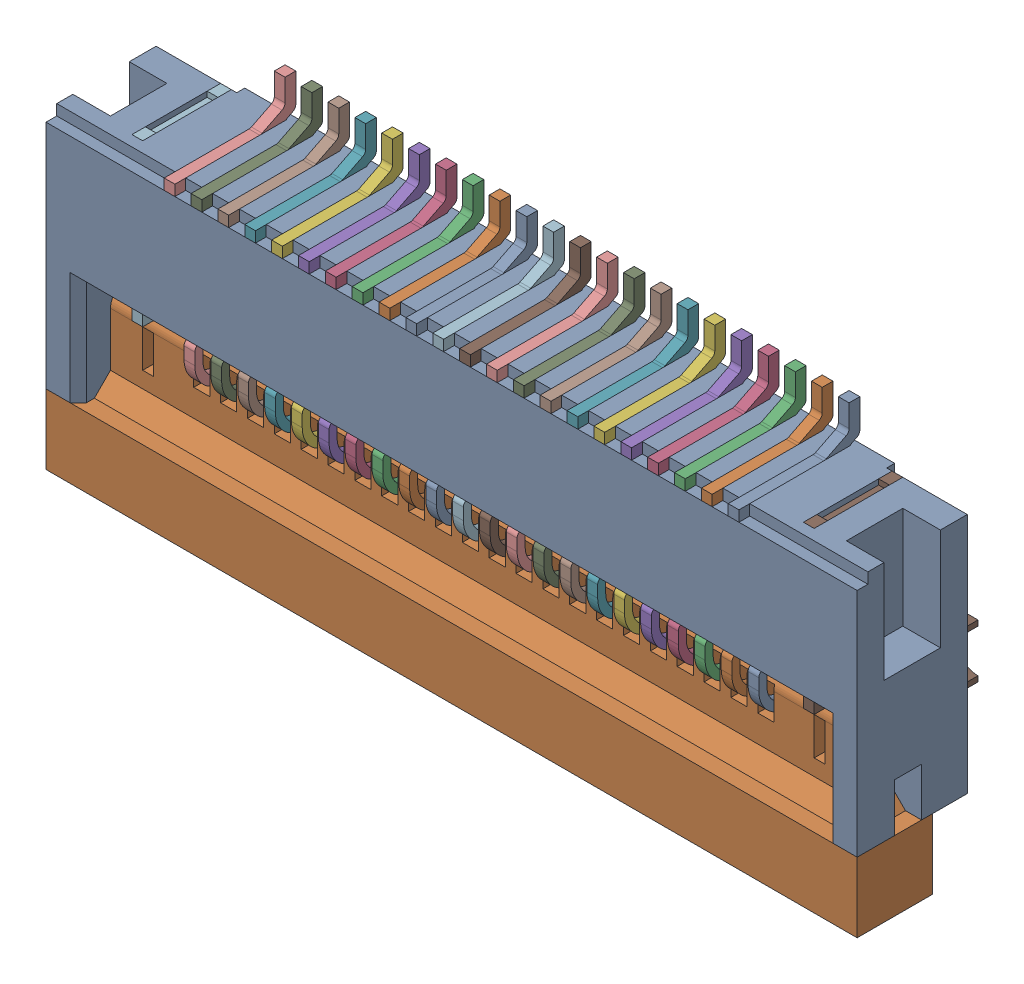
SolidWorks assembly 687122149022, configuration Default. Lengths in mm.
Overall size (15.1 6.5 2.25).
26 component instances, 5 part files, 0 mates.
Components (placement in the parent):
- 6871xx149022_Pin-1: 6871xx149022_Pin [Default] at (5.35 1.125 0.2986) x (-1 0 0) z (0 0 -1) size (0.2 4.6 2.25)
- 6871xx149022_Pin-2: 6871xx149022_Pin [Default] at (4.85 1.125 0.2986) x (-1 0 0) z (0 0 -1) size (0.2 4.6 2.25)
- 6871xx149022_Pin-3: 6871xx149022_Pin [Default] at (4.35 1.125 0.2986) x (-1 0 0) z (0 0 -1) size (0.2 4.6 2.25)
- 6871xx149022_Pin-4: 6871xx149022_Pin [Default] at (3.85 1.125 0.2986) x (-1 0 0) z (0 0 -1) size (0.2 4.6 2.25)
- 6871xx149022_Pin-5: 6871xx149022_Pin [Default] at (3.35 1.125 0.2986) x (-1 0 0) z (0 0 -1) size (0.2 4.6 2.25)
- 6871xx149022_Pin-6: 6871xx149022_Pin [Default] at (2.85 1.125 0.2986) x (-1 0 0) z (0 0 -1) size (0.2 4.6 2.25)
- 6871xx149022_Pin-7: 6871xx149022_Pin [Default] at (2.35 1.125 0.2986) x (-1 0 0) z (0 0 -1) size (0.2 4.6 2.25)
- 6871xx149022_Pin-8: 6871xx149022_Pin [Default] at (1.85 1.125 0.2986) x (-1 0 0) z (0 0 -1) size (0.2 4.6 2.25)
- 6871xx149022_Pin-9: 6871xx149022_Pin [Default] at (1.35 1.125 0.2986) x (-1 0 0) z (0 0 -1) size (0.2 4.6 2.25)
- 6871xx149022_Pin-10: 6871xx149022_Pin [Default] at (0.85 1.125 0.2986) x (-1 0 0) z (0 0 -1) size (0.2 4.6 2.25)
- 6871xx149022_Pin-11: 6871xx149022_Pin [Default] at (0.35 1.125 0.2986) x (-1 0 0) z (0 0 -1) size (0.2 4.6 2.25)
- 6871xx149022_Pin-12: 6871xx149022_Pin [Default] at (-0.15 1.125 0.2986) x (-1 0 0) z (0 0 -1) size (0.2 4.6 2.25)
- 6871xx149022_Pin-13: 6871xx149022_Pin [Default] at (-0.65 1.125 0.2986) x (-1 0 0) z (0 0 -1) size (0.2 4.6 2.25)
- 6871xx149022_Pin-14: 6871xx149022_Pin [Default] at (-1.15 1.125 0.2986) x (-1 0 0) z (0 0 -1) size (0.2 4.6 2.25)
- 6871xx149022_Pin-15: 6871xx149022_Pin [Default] at (-1.65 1.125 0.2986) x (-1 0 0) z (0 0 -1) size (0.2 4.6 2.25)
- 6871xx149022_Pin-16: 6871xx149022_Pin [Default] at (-2.15 1.125 0.2986) x (-1 0 0) z (0 0 -1) size (0.2 4.6 2.25)
- 6871xx149022_Pin-17: 6871xx149022_Pin [Default] at (-2.65 1.125 0.2986) x (-1 0 0) z (0 0 -1) size (0.2 4.6 2.25)
- 6871xx149022_Pin-18: 6871xx149022_Pin [Default] at (-3.15 1.125 0.2986) x (-1 0 0) z (0 0 -1) size (0.2 4.6 2.25)
- 6871xx149022_Pin-19: 6871xx149022_Pin [Default] at (-3.65 1.125 0.2986) x (-1 0 0) z (0 0 -1) size (0.2 4.6 2.25)
- 6871xx149022_Pin-20: 6871xx149022_Pin [Default] at (-4.15 1.125 0.2986) x (-1 0 0) z (0 0 -1) size (0.2 4.6 2.25)
- 6871xx149022_Pin-21: 6871xx149022_Pin [Default] at (-4.65 1.125 0.2986) x (-1 0 0) z (0 0 -1) size (0.2 4.6 2.25)
- 6871xx149022_Pin-22: 6871xx149022_Pin [Default] at (-5.15 1.125 0.2986) x (-1 0 0) z (0 0 -1) size (0.2 4.6 2.25)
- 6871xx149022_Patte-1: 6871xx149022_Patte [Default] at (6.15 0.7 -0.125) x (-1 0 0) z (0 0 1) size (1.4 3.1 1.85)
- 6871xx149022_Patte2-1: 6871xx149022_Patte2 [Default] at (-6.35 0.7 -0.125) x (-1 0 0) z (0 0 1) size (1.4 3.1 1.85)
- 687122149022-1: 687122149022 [Default] at origin size (15.1 4.5 2.2)
- 687122149022_Actuator-1: 687122149022_Actuator [Default] at (0 -2.25 0.4) x (1 0 0) z (0 -1 0) size (15.1 1.4 2.9)
